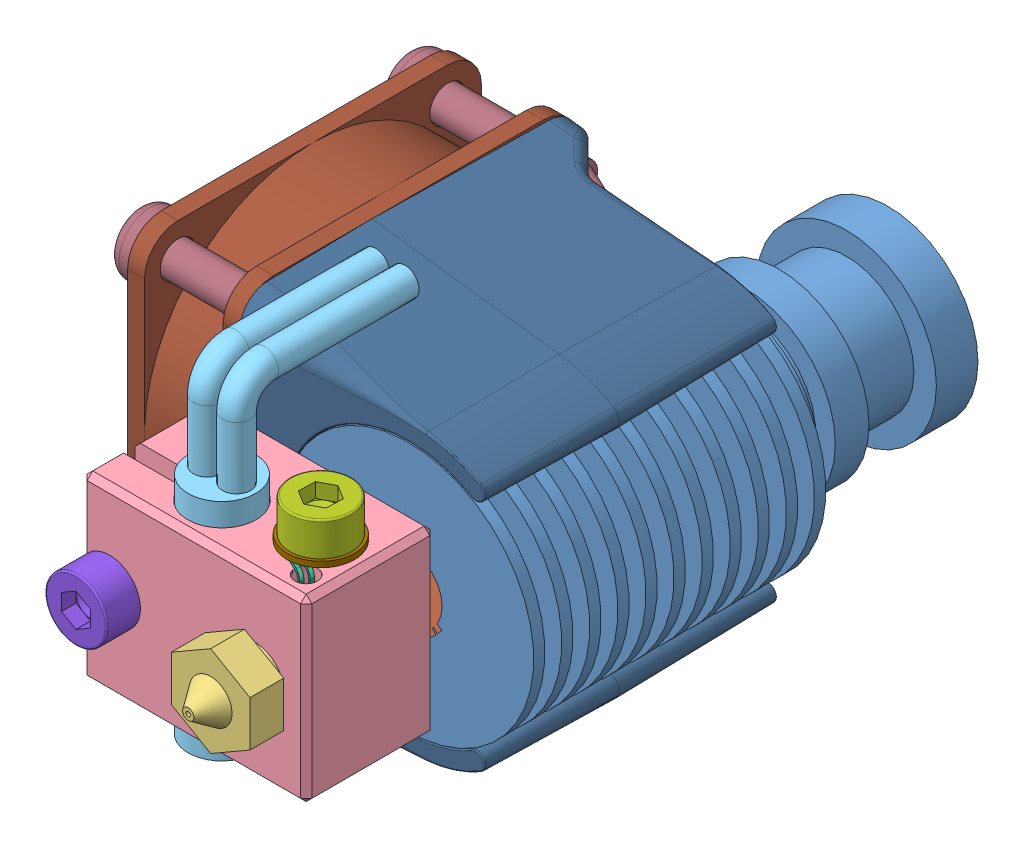
SolidWorks assembly E3D All Metal Hotend V6, configuration Default. Lengths in mm.
Overall size (38.16 34.25 62.3).
17 component instances, 13 part files, 0 mates.
Components (placement in the parent):
- E3D v6 HotEnd - Heatsink-1: E3D v6 HotEnd - Heatsink [Default] at origin size (22.3 22.3 42.7)
- E3D v6 HotEnd - Heatbreak-1: E3D v6 HotEnd - Heatbreak [Default] at (0 0 7.1) size (7 7 21.9)
- E3D v6 HotEnd - Nozzle-1: E3D v6 HotEnd - Nozzle [Default] at (0 0 17.6) x (0.866025 0.5 0) z (0 0 1) size (8.08 7 12.5)
- E3D v6 HotEnd - Heat Block-1: E3D v6 HotEnd - Heat Block [Default] at (-15.5 8 13.6) x (1 0 0) z (0 1 0) size (20 11.5 16)
- Ceramic Cartridge Heater-1: Ceramic Cartridge Heater [Default] at (-7 10 9.6) x (1 0 0) z (0 1 0) size (6 18 29.25)
- Thermistor-1: Thermistor [Default] at (2.5 3.65 11.6) x (0.903857 0 0.427835) z (0 -1 0) size (4.52 1.5 4.65)
- HEXAGON SOCKET HEAD CAP SCREWS_SCB3-4-1: HEXAGON SOCKET HEAD CAP SCREWS_SCB3-4 [Default] at (1 9 8.8) x (0.999538 0 0.030402) z (0 1 0) size (5.5 5.5 7)
- HEXAGON SOCKET HEAD CAP SCREWS_SCB3-10-1: HEXAGON SOCKET HEAD CAP SCREWS_SCB3-10 [Default] at (-13 0 13.6) size (5.5 5.5 13)
- Flat Washers_PWF3-1: Flat Washers_PWF3 [Default] at (1 9 8.8) x (1 0 0) z (0 1 0) size (6 6 0.5)
- E3D-v6 Fan Duct-1: E3D-v6 Fan Duct [Default] x (1 0 0) z (0 1 0) size (22.31 30.04 30)
- Fan-DC-KDE0503PFB3-Promoco_Fan-DC-KDE0503PFB3-Promoco-1: Fan-DC-KDE0503PFB3-Promoco_Fan-DC-KDE0503PFB3-Promoco [Default] at (-15 0 -15) x (0 0 -1) z (-1 0 0) size (30 30 10)
  - Fan-House-30x30x10-Promoco_Fan-House-KDE0503PFB3-Promoco-1: Fan-House-30x30x10-Promoco_Fan-House-KDE0503PFB3-Promoco [Default] at origin size (30 30 10)
  - Fan-30x30x10-Promoco_Fan-KDE0503PFB3-Promoco-1: Fan-30x30x10-Promoco_Fan-KDE0503PFB3-Promoco [Default] x (0 0 -1) z (-0.999131 0.04169 0) size (8.5 27.91 28)
- Self Tapping Screws - Pan Head_CSPTRSA-SUS-TP3-16-1: Self Tapping Screws - Pan Head_CSPTRSA-SUS-TP3-16 [Default] at (-25 -12 -27) size (18.01 5.5 5.5)
- Self Tapping Screws - Pan Head_CSPTRSA-SUS-TP3-16-2: Self Tapping Screws - Pan Head_CSPTRSA-SUS-TP3-16 [Default] at (-25 12 -27) size (18.01 5.5 5.5)
- Self Tapping Screws - Pan Head_CSPTRSA-SUS-TP3-16-3: Self Tapping Screws - Pan Head_CSPTRSA-SUS-TP3-16 [Default] at (-25 12 -3) size (18.01 5.5 5.5)
- Self Tapping Screws - Pan Head_CSPTRSA-SUS-TP3-16-4: Self Tapping Screws - Pan Head_CSPTRSA-SUS-TP3-16 [Default] at (-25 -12 -3) size (18.01 5.5 5.5)
